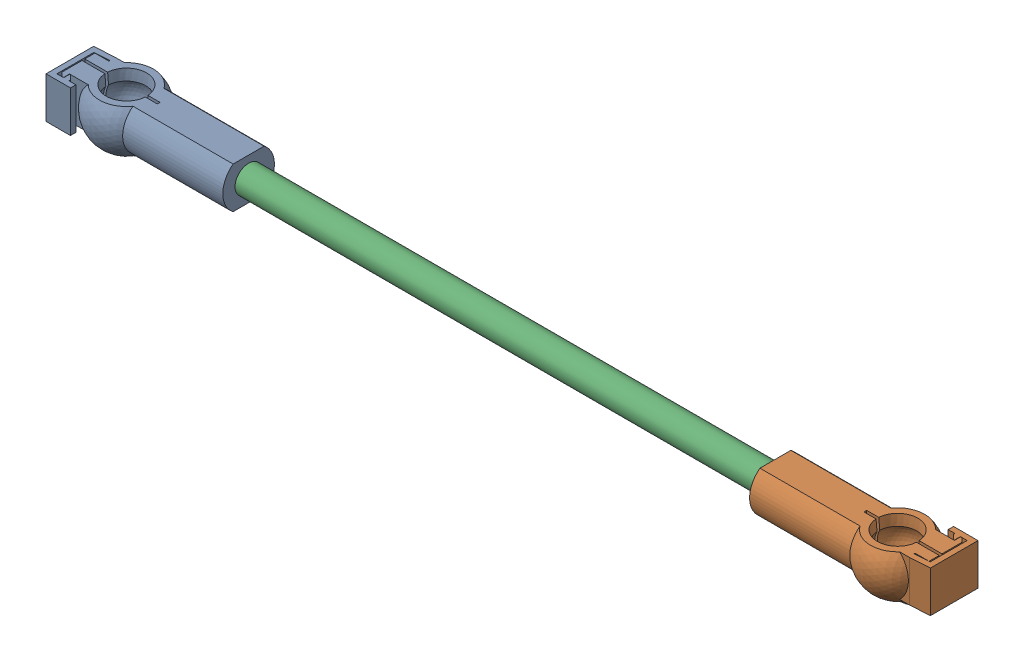
SolidWorks assembly SE_TigeCapteur, configuration Default. Lengths in mm.
Overall size (160.24 10.8 12.5).
3 component instances, 2 part files, 6 mates.
Components (placement in the parent):
- RotuleClipEnveloppe-1: RotuleClipEnveloppe [Default] at origin size (31.62 10.8 12.5)
- RotuleClipEnveloppe-2: RotuleClipEnveloppe [Default] at (142 0 0) x (-1 0 0) z (0 0 -1) size (31.62 10.8 12.5)
- TigeCapteur-1: TigeCapteur [Default] at (9.5 0 0) x (0 0 -1) z (1 0 0) size (5 5 123)
Mates (geometry in assembly coordinates):
- Coïncidente1: coincident anti-aligned: plane of RotuleClipEnveloppe-2 through (132.5 0 0) normal (-1 0 0); plane of TigeCapteur-1 through (132.5 0 0) normal (1 0 0)
- Coïncidente2: coincident anti-aligned: plane of assembly through (9.5 0 0) normal (1 0 0); plane of TigeCapteur-1 through (9.5 0 0) normal (-1 0 0)
- Coaxial1: concentric aligned: cylinder of assembly through (132.5 0 0) axis (-1 0 0) radius 2.5; cylinder of assembly through (132.5 0 0) axis (-1 0 0) radius 2.5
- Coaxial2: concentric anti-aligned: cylinder of assembly through (9.5 0 0) axis (1 0 0) radius 2.5; cylinder of assembly through (132.5 0 0) axis (-1 0 0) radius 2.5
- Parallèle1: parallel aligned: plane of assembly through (0 0 0) normal (0 0 1); plane of RotuleClipEnveloppe-1 through (-0.4931 3.8 4.6871) normal (0 1 0)
- Parallèle2: parallel anti-aligned: plane of ?; plane of ?
